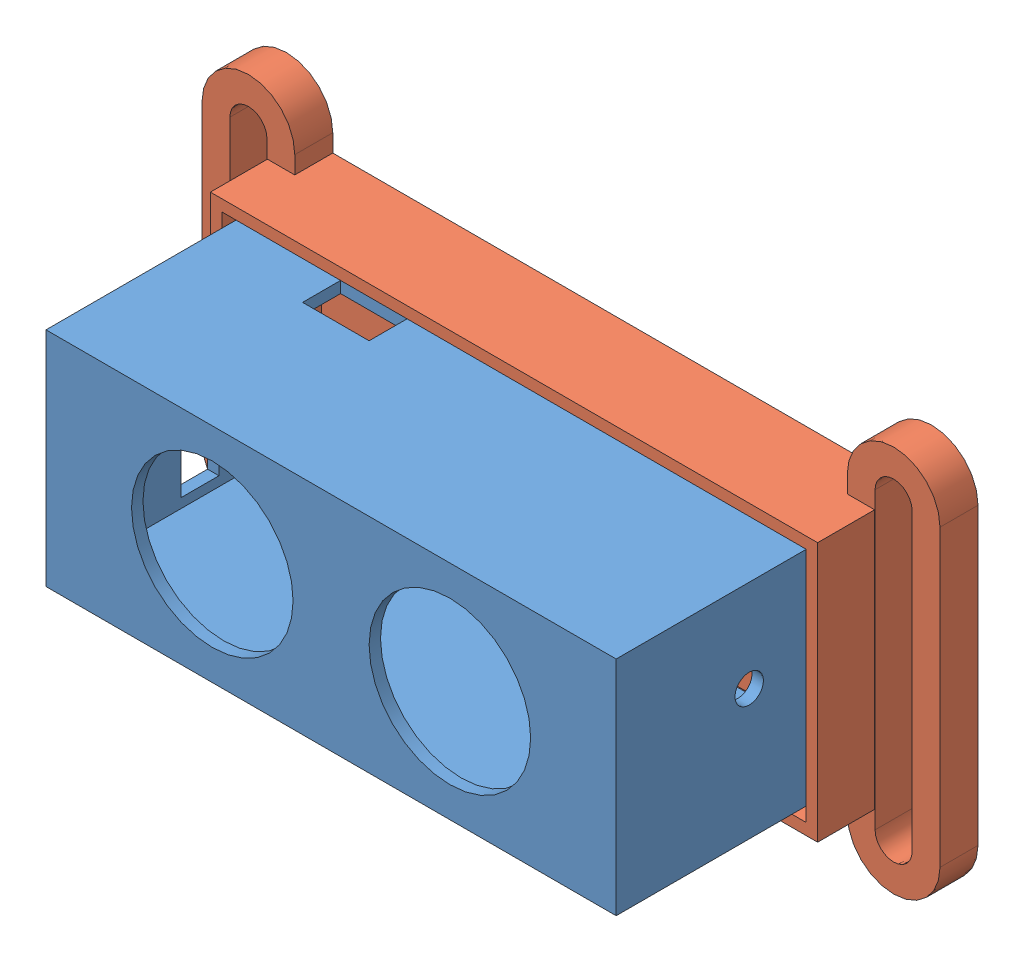
SolidWorks assembly ensamblaje, configuration Default. Lengths in mm.
Overall size (77.65 40.75 30).
2 component instances, 2 part files, 3 mates.
Components (placement in the parent):
- base1-1: base1 [Default] at (-0.0756 19.8854 74.6425) size (60 23.4 26)
- base2-1: base2 [Default] at (13.114 15.4069 44.6425) size (77.65 40.75 10)
Mates (geometry in assembly coordinates):
- Coincident4: coincident: plane of assembly; plane of assembly; plane of base1-1 through (-25.8162 34.2142 74.6425) normal (0 1 0); plane of base2-1 through (-27.3162 34.2142 44.6425) normal (0 -1 0)
- Coincident5: coincident: plane of assembly; plane of assembly; plane of base1-1 through (34.1838 34.2142 74.6425) normal (1 0 0); plane of base2-1 through (34.1838 34.2142 44.6425) normal (-1 0 0)
- Coincident6: coincident: plane of assembly; plane of assembly; plane of base1-1 through (-0.0756 19.8854 48.6425) normal (0 0 -1); plane of base2-1 through (13.114 15.4069 48.6425) normal (0 0 1)
